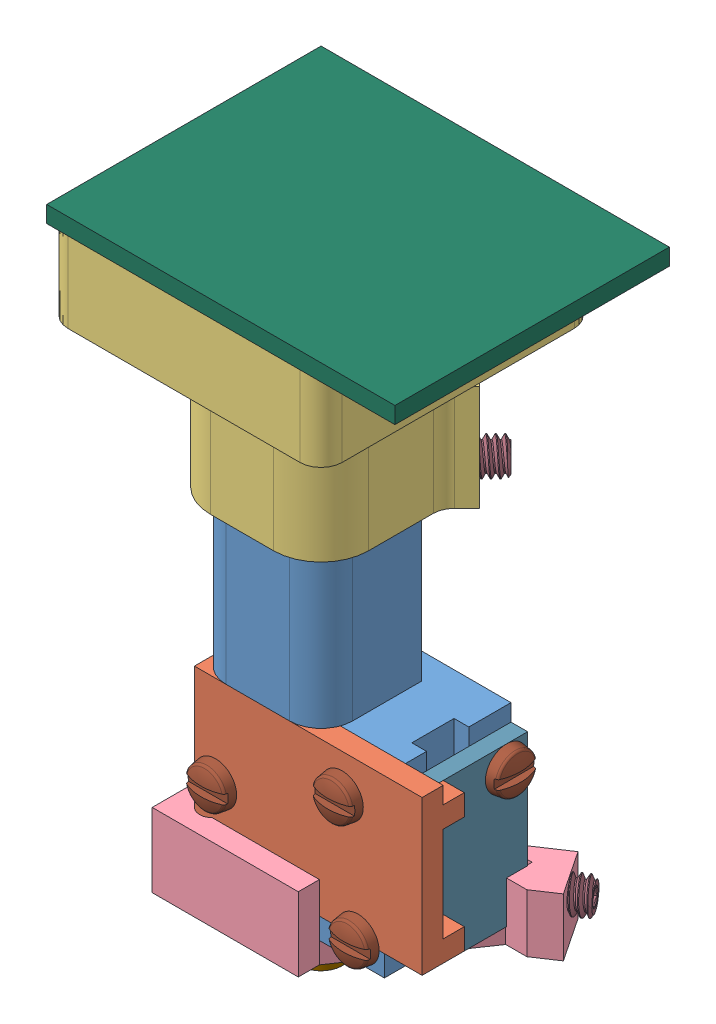
SolidWorks assembly MiniscopeAssembly, configuration Default. Lengths in mm.
Overall size (16.5 30.74 13).
24 component instances, 15 part files, 44 mates.
Components (placement in the parent):
- MS_MainBodyv3-1: MS_MainBodyv3 [Default] at origin size (9 17.3 6)
- MS_FilterCoverv3-1: MS_FilterCoverv3 [Default] at (0 4.25 3) x (-1 0 0) z (0 0 -1) size (10.79 7.3 2)
- MS_FocusSliderv3-1: MS_FocusSliderv3 [Default] at (-1.5 15.6547 0) size (13 10.8 13)
- MS_Baseplatev3-1: MS_Baseplatev3 [Default] at (0.25 -1 -0.25) x (0 0 1) z (-1 0 0) size (9.02 3.5 12.54)
- Achromatic_Lens_5mmD-1: Achromatic_Lens_5mmD [Default] at (-1.5 11.38 0) x (0.964992 0 -0.26228) z (0 -1 0) size (5.14 5.1 2.58)
- Dichroic-1: Dichroic [Default] at (-1.6211 4.3638 0) x (-0.707107 -0.707107 0) z (0 0 1) size (6 1.05 4)
- Emission_Filter-1: Emission_Filter [Default] at (-1.5 7.1 0) size (4 1.05 4)
- Excitation_Filter-1: Excitation_Filter [Default] at (1.25 2.75 0) x (0 -1 0) z (0 0 1) size (3.5 1.05 4)
- GRIN_2mmD_5mmL-1: GRIN_2mmD_5mmL [Default] at (-1.5 -3.5 0) size (2 5 2)
- Lens_3mm_HalfSphere_Edmund-1: Lens_3mm_HalfSphere_Edmund [Default] at (3.8 3 0) x (0 1 0) z (0 0 1) size (3 1.5 3)
- m1_3mm_screw-1: m1_3mm_screw [91800A056] at (5.2874 6.5 -2) x (0 0.007127 -0.999975) z (1 0 0) size (2 2 3.76)
- Magnetic_Disk-1: Magnetic_Disk [Default] at (-3.25 -1 1.875) size (1.59 0.79 1.59)
- Set_Screw_0_80-1: Set_Screw_0_80 [92311A051] at (2.2411 16.9047 -3.7411) x (-0.675901 0.293797 -0.675901) z (0.707107 0 -0.707107) size (1.76 1.55 2.51)
- m1_3mm_screw-2: m1_3mm_screw [91800A056] at (3.25 1 3) size (2 2 3.76)
- m1_3mm_screw-3: m1_3mm_screw [91800A056] at (-3.5 4 3) size (2 2 3.76)
- m1_3mm_screw-4: m1_3mm_screw [91800A056] at (2.5 6.5 3) size (2 2 3.76)
- Set_Screw_0_80-2: Set_Screw_0_80 [92311A051] at (6.1624 0.875 -3.8582) x (-0.265868 0.877651 -0.398803) z (0.83205 0 -0.5547) size (1.76 1.55 2.51)
- Magnetic_Disk-2: Magnetic_Disk [Default] at (-3.25 -1 -1.875) size (1.59 0.79 1.59)
- Magnetic_Disk-3: Magnetic_Disk [Default] at (-3.25 0 1.875) size (1.59 0.79 1.59)
- Magnetic_Disk-4: Magnetic_Disk [Default] at (-3.25 0 -1.875) size (1.59 0.79 1.59)
- Magnetic_Disk-5: Magnetic_Disk [Default] at (1.5 0 0) size (1.59 0.79 1.59)
- Magnetic_Disk-6: Magnetic_Disk [Default] at (1.5 -1 0) size (1.59 0.79 1.59)
- LED_PCB-1: LED_PCB [Default] at (5.2874 3 0) x (0 0 -1) z (0 1 0) size (5 1.49 7.5)
- CMOS_Imaging_Sensor_PCB-1: CMOS_Imaging_Sensor_PCB [Default] at (0.25 27.2421 0) x (0 0 1) z (1 0 0) size (13 3.09 16.5)
Mates (geometry in assembly coordinates):
- Coincident1: coincident anti-aligned: plane of MS_MainBodyv3-1 through (1.2426 5.7426 -10.6971) normal (-0.707107 0.707107 0); plane of Dichroic-1 through (-0.8787 3.6213 0) normal (0.707107 -0.707107 0)
- Coincident2: coincident aligned: line of MS_MainBodyv3-1 through (1.2426 5.7426 -2) axis (0 0 1); line of Dichroic-1 through (1.2426 5.7426 -2) axis (0 0 1)
- Coincident3: coincident anti-aligned: plane of MS_MainBodyv3-1 through (4.5 8.3 -2) normal (0 0 1); plane of Dichroic-1 through (-3 1.5 -2) normal (0 0 -1)
- Coincident4: coincident anti-aligned: plane of MS_MainBodyv3-1 through (2.3 4.5 -10.6971) normal (-1 0 0); plane of Excitation_Filter-1 through (2.3 2.75 0) normal (1 0 0)
- Coincident5: coincident anti-aligned: plane of MS_MainBodyv3-1 through (4.5 8.3 -2) normal (0 0 1); plane of Excitation_Filter-1 through (2.3 1 -2) normal (0 0 -1)
- Coincident6: coincident anti-aligned: line of MS_MainBodyv3-1 through (2.3 1 -2) axis (0 0 1); line of Excitation_Filter-1 through (2.3 1 2) axis (0 0 -1)
- Coincident7: coincident anti-aligned: plane of MS_MainBodyv3-1 through (0.5 7.1 -10.6971) normal (0 1 0); plane of Emission_Filter-1 through (-1.5 7.1 0) normal (0 -1 0)
- Coincident8: coincident anti-aligned: line of MS_MainBodyv3-1 through (0.5 7.1 -2) axis (0 0 1); line of Emission_Filter-1 through (0.5 7.1 2) axis (0 0 -1)
- Coincident9: coincident anti-aligned: plane of MS_MainBodyv3-1 through (4.5 8.3 -2) normal (0 0 1); plane of Emission_Filter-1 through (0.5 8.15 -2) normal (0 0 -1)
- Coincident10: coincident anti-aligned: plane of MS_MainBodyv3-1 through (0 0 2) normal (0 0 1); plane of MS_FilterCoverv3-1 through (3.25 1 2) normal (0 0 -1)
- Coincident11: coincident anti-aligned: plane of MS_MainBodyv3-1 through (4.5 1 2) normal (0 1 0); plane of MS_FilterCoverv3-1 through (3.75 1 2) normal (0 -1 0)
- Coincident12: coincident aligned: plane of MS_MainBodyv3-1 through (-4.5 8.3 -3) normal (-1 0 0); plane of MS_FilterCoverv3-1 through (-4.5 7.5 2) normal (-1 0 0)
- Coincident13: coincident anti-aligned: plane of MS_MainBodyv3-1 through (-4.5 8.3 -3) normal (-1 0 0); plane of MS_FocusSliderv3-1 through (-4.5 26.4547 -3) normal (1 0 0)
- Coincident14: coincident anti-aligned: plane of MS_MainBodyv3-1 through (4.5 8.3 3) normal (0 0 1); plane of MS_FocusSliderv3-1 through (-4.5 26.4547 3) normal (0 0 -1)
- Coincident15: coincident anti-aligned: circle of MS_MainBodyv3-1; circle of Lens_3mm_HalfSphere_Edmund-1
- Concentric1: concentric anti-aligned: cylinder of MS_MainBodyv3-1 through (-1.5 1.2289 0) axis (0 1 0) radius 2.5; cylinder of Achromatic_Lens_5mmD-1 through (-1.5 10.3334 0) axis (0 -1 0) radius 2.5
- Tangent1: tangent: plane of MS_MainBodyv3-1 through (4.5 8.8 2) normal (0 1 0); face of Achromatic_Lens_5mmD-1
- Coincident16: coincident anti-aligned: plane of MS_MainBodyv3-1 through (0 0 0) normal (0 -1 0); plane of MS_Baseplatev3-1 through (0.25 0 -0.25) normal (0 1 0)
- Coincident18: coincident anti-aligned: plane of MS_MainBodyv3-1 through (4.5 8.3 3) normal (0 0 1); plane of MS_Baseplatev3-1 through (5 -12.5109 3) normal (0 0 -1)
- Coincident19: coincident anti-aligned: plane of MS_MainBodyv3-1 through (-4.5 8.3 -3) normal (-1 0 0); plane of MS_Baseplatev3-1 through (-4.5 -12.5109 3) normal (1 0 0)
- Coincident21: coincident aligned: circle of MS_Baseplatev3-1; circle of Magnetic_Disk-4
- Coincident22: coincident aligned: circle of MS_Baseplatev3-1; circle of Magnetic_Disk-5
- Coincident23: coincident aligned: circle of MS_Baseplatev3-1; circle of Magnetic_Disk-6
- Coincident24: coincident aligned: circle of MS_Baseplatev3-1; circle of Magnetic_Disk-2
- Coincident25: coincident aligned: circle of MS_Baseplatev3-1; circle of Magnetic_Disk-3
- Coincident26: coincident aligned: circle of MS_Baseplatev3-1; circle of Magnetic_Disk-1
- Concentric2: concentric aligned: cylinder of MS_MainBodyv3-1 through (-1.5 17.3 0) axis (0 -1 0) radius 1.25; cylinder of GRIN_2mmD_5mmL-1 through (-1.5 1.5 0) axis (0 -1 0) radius 1
- Distance1: distance = 2.5 mm aligned: plane of GRIN_2mmD_5mmL-1 through (-1.5 -3.5 0) normal (0 -1 0); plane of MS_Baseplatev3-1 through (0.25 -1 -0.25) normal (0 -1 0)
- Concentric3: concentric aligned: circle of MS_FilterCoverv3-1; circle of m1_3mm_screw-3
- Concentric4: concentric aligned: circle of MS_FilterCoverv3-1; circle of m1_3mm_screw-4
- Concentric5: concentric anti-aligned: circle of MS_FilterCoverv3-1; circle of m1_3mm_screw-2
- Concentric6: concentric anti-aligned: circle of MS_MainBodyv3-1; circle of m1_3mm_screw-1
- Coincident29: coincident anti-aligned: plane of MS_FilterCoverv3-1 through (3.25 1 3) normal (0 0 1); plane of m1_3mm_screw-3 through (-3.5 4 3) normal (0 0 -1)
- Coincident30: coincident anti-aligned: plane of MS_FilterCoverv3-1 through (3.25 1 3) normal (0 0 1); circle of m1_3mm_screw-2
- Coincident31: coincident anti-aligned: plane of MS_FilterCoverv3-1 through (3.25 1 3) normal (0 0 1); plane of m1_3mm_screw-4 through (2.5 6.5 3) normal (0 0 -1)
- Concentric7: concentric aligned: circle of MS_FocusSliderv3-1; circle of Set_Screw_0_80-1
- Concentric8: concentric aligned: circle of MS_Baseplatev3-1; circle of Set_Screw_0_80-2
- Parallel2: parallel aligned: line of MS_MainBodyv3-1 through (4.5 2 -3) axis (0 0 1); line of LED_PCB-1 through (4.5 2 -3) axis (0 0 1)
- Coincident35: coincident anti-aligned: plane of MS_MainBodyv3-1 through (4.5 8.3 -3) normal (1 0 0); plane of LED_PCB-1 through (4.5 3 0) normal (-1 0 0)
- Concentric9: concentric anti-aligned: cylinder of MS_MainBodyv3-1 through (2 6.5 -2) axis (1 0 0) radius 0.375; cylinder of LED_PCB-1 through (5.2874 6.5 -2) axis (-1 0 0) radius 0.5
- Coincident36: coincident anti-aligned: plane of m1_3mm_screw-1 through (5.2874 6.5 -2) normal (-1 0 0); plane of LED_PCB-1 through (5.2874 3 0) normal (1 0 0)
- Coincident37: coincident anti-aligned: plane of MS_FocusSliderv3-1 through (-1.5 26.4547 0) normal (0 1 0); plane of CMOS_Imaging_Sensor_PCB-1 through (0.25 26.4547 0) normal (0 -1 0)
- Coincident38: coincident aligned: plane of MS_FocusSliderv3-1 through (-8 26.4547 -6.5) normal (-1 0 0); plane of CMOS_Imaging_Sensor_PCB-1 through (-8 26.4547 6.5) normal (-1 0 0)
- Coincident39: coincident aligned: plane of MS_FocusSliderv3-1 through (5 26.4547 6.5) normal (0 0 1); plane of CMOS_Imaging_Sensor_PCB-1 through (-8 26.4547 6.5) normal (0 0 1)
